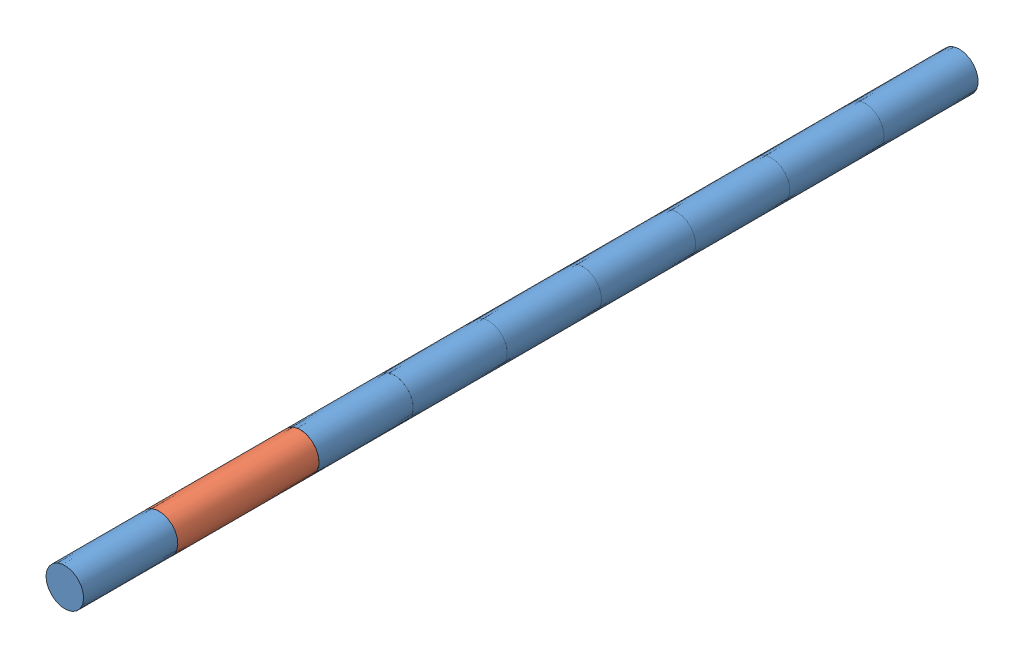
SolidWorks assembly Assem1, configuration Default. Lengths in mm.
Overall size (5.52 5.52 95).
9 component instances, 2 part files, 8 mates.
Components (placement in the parent):
- base-2: base [Default] at (1.2169 5.9095 3.534) x (-0.535333 -0.844641 0) z (0.844641 -0.535333 0) size (4 10 4)
- base-3: base [Default] at (1.2169 5.9095 -6.466) x (-0.421922 -0.906632 0) z (0.906632 -0.421922 0) size (4 10 4)
- base-4: base [Default] at (1.2169 5.9095 -26.466) x (1 0 0) z (0 1 0) size (4 10 4)
- base-5: base [Default] at (1.2169 5.9095 -26.466) x (1 0 0) z (0 -1 0) size (4 10 4)
- base-6: base [Default] at (1.2169 5.9095 -46.466) x (1 0 0) z (0 -1 0) size (4 10 4)
- base-7: base [Default] at (1.2169 5.9095 -46.466) x (1 0 0) z (0 1 0) size (4 10 4)
- base-8: base [Default] at (1.2169 5.9095 -66.466) x (1 0 0) z (0 -1 0) size (4 10 4)
- tll-1: tll [Default] at (1.2169 5.9095 3.534) x (-0.923728 -0.383049 0) z (-0.383049 0.923728 0) size (4 15 4)
- base-9: base [Default] at (1.2169 5.9095 18.534) x (-0.923728 -0.383049 0) z (-0.383049 0.923728 0) size (4 10 4)
Mates (geometry in assembly coordinates):
- Coincident3: coincident aligned: circle of base-2; circle of base-3
- Coincident4: coincident anti-aligned: circle of base-3; circle of base-5
- Coincident5: coincident anti-aligned: circle of base-4; circle of base-5
- Coincident6: coincident anti-aligned: circle of base-4; circle of base-6
- Coincident7: coincident anti-aligned: circle of base-6; circle of base-7
- Coincident8: coincident anti-aligned: circle of base-7; circle of base-8
- Coincident11: coincident anti-aligned: circle of base-2; circle of tll-1
- Coincident12: coincident aligned: circle of tll-1; circle of base-9
